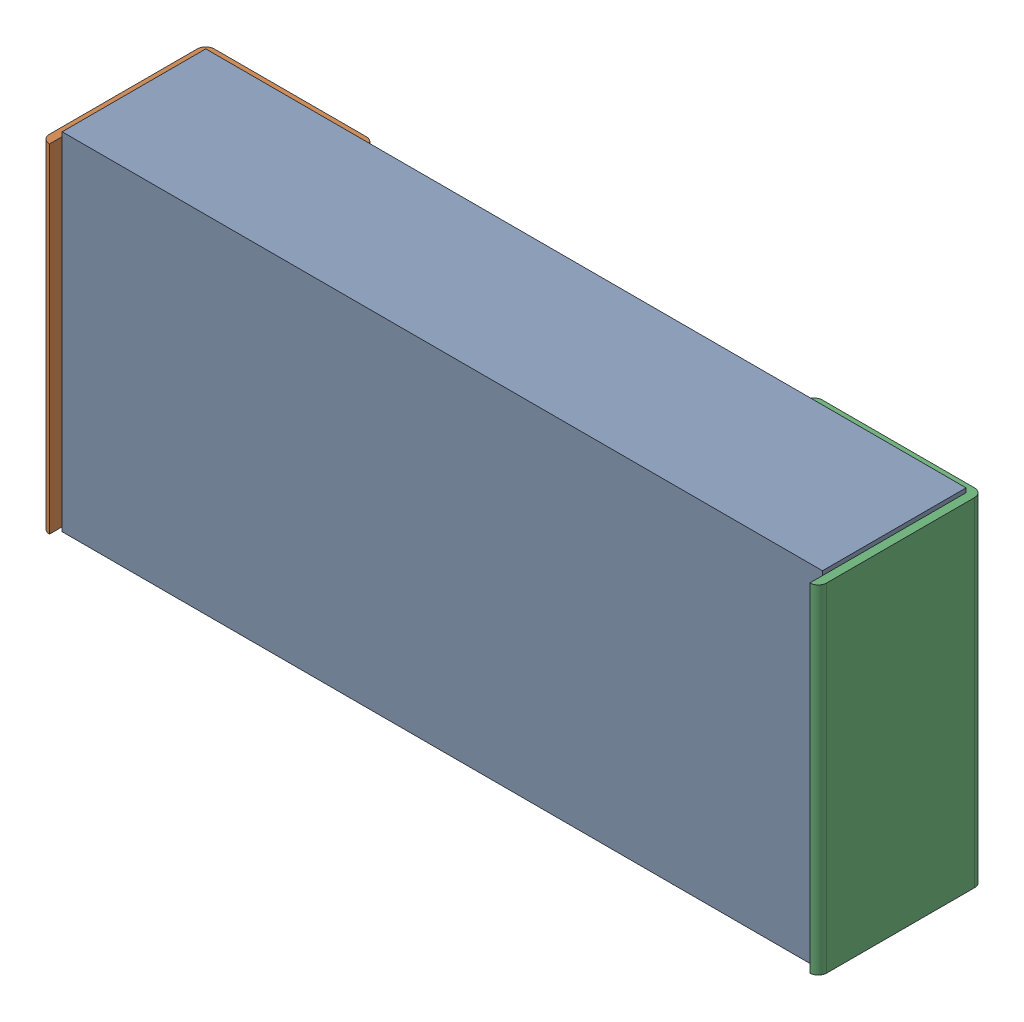
SolidWorks assembly C5, configuration Predeterminado. Lengths in mm.
Overall size (2.34 1.04 0.5).
4 component instances, 3 part files, 0 mates.
Components (placement in the parent):
- Open CASCADE STEP translator 6.8 1.5.1-1: Open CASCADE STEP translator 6.8 1.5.1 [Predeterminado] at origin size (2.34 1.04 0.5)
  - Body_1_2-1: Body_1_2 [Predeterminado] at origin size (2.29 1.04 0.43)
  - Pin_1_2-1: Pin_1_2 [Predeterminado] at (0.3048 0 0) x (-1 0 0) z (0 0 1) size (0.51 1.02 0.5)
  - Pin_2_2-1: Pin_2_2 [Predeterminado] at origin size (0.51 1.02 0.5)
